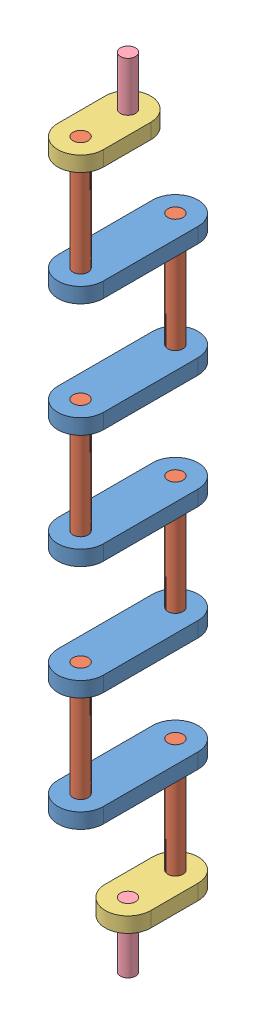
SolidWorks assembly Modular_Shaft_593368a, configuration  . Lengths in mm.
Overall size (12 210 37).
15 component instances, 4 part files, 28 mates.
Components (placement in the parent):
- Shaft_Ligament_593368a-1: Shaft_Ligament_593368a [Default] at (0 30 12.5) size (12 4 37)
- Shaft_Bone_593368a-2: Shaft_Bone_593368a [Default] at origin size (4 34 4)
- Shaft_Bone_593368a-3: Shaft_Bone_593368a [Default] at (0 30 25) size (4 34 4)
- Shaft_Bone_593368a-4: Shaft_Bone_593368a [Default] at (0 60 0) size (4 34 4)
- Shaft_Bone_593368a-5: Shaft_Bone_593368a [Default] at (0 90 25) size (4 34 4)
- Shaft_Bone_593368a-6: Shaft_Bone_593368a [Default] at (0 120 0) size (4 34 4)
- Shaft_Bone_593368a-7: Shaft_Bone_593368a [Default] at (0 150 25) size (4 34 4)
- Shaft_Ligament_593368a-2: Shaft_Ligament_593368a [Default] at (0 60 12.5) size (12 4 37)
- Shaft_Ligament_593368a-3: Shaft_Ligament_593368a [Default] at (0 90 12.5) size (12 4 37)
- Shaft_Ligament_593368a-4: Shaft_Ligament_593368a [Default] at (0 120 12.5) size (12 4 37)
- Shaft_Ligament_593368a-5: Shaft_Ligament_593368a [Default] at (0 150 12.5) size (12 4 37)
- Shaft_Ligament_short_593368a-1: Shaft_Ligament_short_593368a [Default] at (0 180 18.75) size (12 4 24.5)
- Shaft_Ligament_short_593368a-2: Shaft_Ligament_short_593368a [Default] at (0 0 6.25) size (12 4 24.5)
- Shaft_Bone_Small_593368a-8: Shaft_Bone_Small_593368a [Default] at (0 -13 12.5) size (4 17 4)
- Shaft_Bone_Small_593368a-9: Shaft_Bone_Small_593368a [Default] at (0 180 12.5) size (4 17 4)
Mates (geometry in assembly coordinates):
- Concentric1: concentric anti-aligned: cylinder of Shaft_Ligament_593368a-1 through (0 30 0) axis (0 1 0) radius 2; cylinder of Shaft_Bone_593368a-2 through (0 34 0) axis (0 -1 0) radius 2
- Coincident3: coincident aligned: plane of Shaft_Ligament_593368a-1 through (0 34 0) normal (0 1 0); plane of Shaft_Bone_593368a-2 through (0 34 0) normal (0 1 0)
- Coincident4: coincident anti-aligned: circle of Shaft_Ligament_593368a-1; cylinder of Shaft_Bone_593368a-3 through (0 64 25) axis (0 -1 0) radius 2
- Coincident5: coincident aligned: plane of Shaft_Ligament_593368a-1 through (0 30 0) normal (0 -1 0); plane of Shaft_Bone_593368a-3 through (0 30 25) normal (0 -1 0)
- Concentric2: concentric anti-aligned: cylinder of Shaft_Bone_593368a-3 through (0 64 25) axis (0 -1 0) radius 2; cylinder of Shaft_Ligament_593368a-2 through (0 60 25) axis (0 1 0) radius 2
- Coincident6: coincident aligned: plane of Shaft_Bone_593368a-3 through (0 64 25) normal (0 1 0); circle of Shaft_Ligament_593368a-2
- Concentric3: concentric anti-aligned: cylinder of Shaft_Bone_593368a-4 through (0 94 0) axis (0 -1 0) radius 2; cylinder of Shaft_Ligament_593368a-2 through (0 60 0) axis (0 1 0) radius 2
- Coincident7: coincident aligned: plane of Shaft_Bone_593368a-4 through (0 60 0) normal (0 -1 0); plane of Shaft_Ligament_593368a-2 through (0 60 0) normal (0 -1 0)
- Concentric4: concentric anti-aligned: cylinder of Shaft_Bone_593368a-4 through (0 94 0) axis (0 -1 0) radius 2; cylinder of Shaft_Ligament_593368a-3 through (0 90 0) axis (0 1 0) radius 2
- Coincident8: coincident aligned: plane of Shaft_Bone_593368a-4 through (0 94 0) normal (0 1 0); plane of Shaft_Ligament_593368a-3 through (0 94 0) normal (0 1 0)
- Concentric5: concentric anti-aligned: cylinder of Shaft_Bone_593368a-5 through (0 124 25) axis (0 -1 0) radius 2; cylinder of Shaft_Ligament_593368a-3 through (0 90 25) axis (0 1 0) radius 2
- Coincident9: coincident aligned: plane of Shaft_Bone_593368a-5 through (0 90 25) normal (0 -1 0); plane of Shaft_Ligament_593368a-3 through (0 90 0) normal (0 -1 0)
- Concentric6: concentric anti-aligned: cylinder of Shaft_Bone_593368a-5 through (0 124 25) axis (0 -1 0) radius 2; cylinder of Shaft_Ligament_593368a-4 through (0 120 25) axis (0 1 0) radius 2
- Coincident10: coincident aligned: plane of Shaft_Bone_593368a-5 through (0 124 25) normal (0 1 0); plane of Shaft_Ligament_593368a-4 through (0 124 0) normal (0 1 0)
- Concentric7: concentric anti-aligned: cylinder of Shaft_Bone_593368a-6 through (0 154 0) axis (0 -1 0) radius 2; cylinder of Shaft_Ligament_593368a-4 through (0 120 0) axis (0 1 0) radius 2
- Coincident11: coincident aligned: plane of Shaft_Bone_593368a-6 through (0 120 0) normal (0 -1 0); plane of Shaft_Ligament_593368a-4 through (0 120 0) normal (0 -1 0)
- Concentric8: concentric anti-aligned: cylinder of Shaft_Bone_593368a-6 through (0 154 0) axis (0 -1 0) radius 2; cylinder of Shaft_Ligament_593368a-5 through (0 150 0) axis (0 1 0) radius 2
- Coincident12: coincident aligned: plane of Shaft_Bone_593368a-6 through (0 154 0) normal (0 1 0); plane of Shaft_Ligament_593368a-5 through (0 154 0) normal (0 1 0)
- Coincident13: coincident aligned: plane of Shaft_Bone_593368a-7 through (0 150 25) normal (0 -1 0); plane of Shaft_Ligament_593368a-5 through (0 150 0) normal (0 -1 0)
- Concentric9: concentric anti-aligned: cylinder of Shaft_Bone_593368a-7 through (0 184 25) axis (0 -1 0) radius 2; cylinder of Shaft_Ligament_593368a-5 through (0 150 25) axis (0 1 0) radius 2
- Concentric10: concentric anti-aligned: cylinder of Shaft_Bone_593368a-7 through (0 184 25) axis (0 -1 0) radius 2; cylinder of Shaft_Ligament_short_593368a-1 through (0 180 25) axis (0 1 0) radius 2
- Coincident14: coincident aligned: plane of Shaft_Bone_593368a-7 through (0 184 25) normal (0 1 0); plane of Shaft_Ligament_short_593368a-1 through (0 184 12.5) normal (0 1 0)
- Concentric11: concentric anti-aligned: cylinder of Shaft_Bone_593368a-2 through (0 34 0) axis (0 -1 0) radius 2; cylinder of Shaft_Ligament_short_593368a-2 through (0 0 0) axis (0 1 0) radius 2
- Coincident15: coincident aligned: plane of Shaft_Bone_593368a-2 through (0 0 0) normal (0 -1 0); plane of Shaft_Ligament_short_593368a-2 through (0 0 0) normal (0 -1 0)
- Concentric12: concentric anti-aligned: cylinder of Shaft_Ligament_short_593368a-1 through (0 180 12.5) axis (0 1 0) radius 2; cylinder of Shaft_Bone_Small_593368a-9 through (0 197 12.5) axis (0 -1 0) radius 2
- Coincident16: coincident aligned: plane of Shaft_Ligament_short_593368a-1 through (0 180 12.5) normal (0 -1 0); plane of Shaft_Bone_Small_593368a-9 through (0 180 12.5) normal (0 -1 0)
- Concentric13: concentric anti-aligned: cylinder of Shaft_Ligament_short_593368a-2 through (0 0 12.5) axis (0 1 0) radius 2; cylinder of Shaft_Bone_Small_593368a-8 through (0 4 12.5) axis (0 -1 0) radius 2
- Coincident17: coincident aligned: plane of Shaft_Ligament_short_593368a-2 through (0 4 0) normal (0 1 0); plane of Shaft_Bone_Small_593368a-8 through (0 4 12.5) normal (0 1 0)
